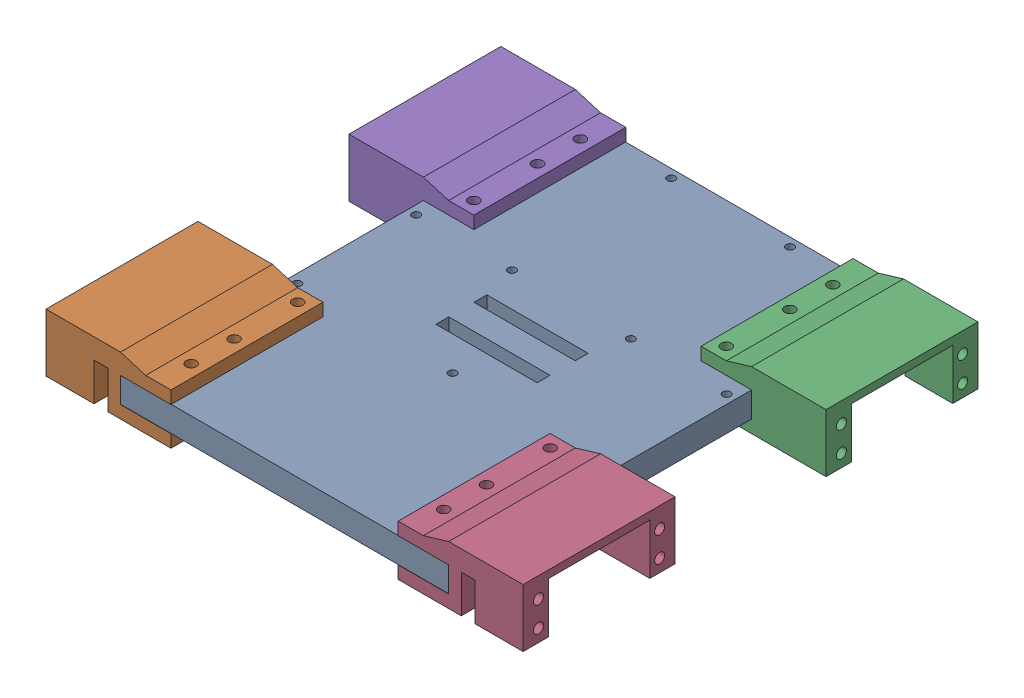
SolidWorks assembly Base_with_lateral_housings, configuration Default. Lengths in mm.
Overall size (189 23 180.2).
5 component instances, 3 part files, 8 mates.
Components (placement in the parent):
- Base_centric-1: Base_centric [Default] at origin size (130 10 180)
- Lateral_mount-1: Lateral_mount [Default] at (-94.5 -5 80.1) size (49.5 23 60.2)
- Lateral_mount-2: Lateral_mount [Default] at (94.5 -5 -80.1) x (-1 0 0) z (0 0 -1) size (49.5 23 60.2)
- Lateral_mount_mirrored-1: Lateral_mount_mirrored [Default] at (94.5 -5 80.1) size (49.5 23 60.2)
- Lateral_mount_mirrored-2: Lateral_mount_mirrored [Default] at (-94.5 -5 -80.1) x (-1 0 0) z (0 0 -1) size (49.5 23 60.2)
Mates (geometry in assembly coordinates):
- Concentric2: concentric anti-aligned: circle of Base_centric-1; circle of Lateral_mount_mirrored-1
- Coincident3: coincident anti-aligned: plane of Base_centric-1 through (0 10 0) normal (0 1 0); plane of Lateral_mount_mirrored-1 through (45 10 90.1) normal (0 -1 0)
- Concentric4: concentric anti-aligned: circle of Base_centric-1; circle of Lateral_mount-1
- Coincident6: coincident anti-aligned: plane of Base_centric-1 through (0 10 0) normal (0 1 0); plane of Lateral_mount-1 through (-45 10 90.1) normal (0 -1 0)
- Concentric6: concentric anti-aligned: circle of Base_centric-1; circle of Lateral_mount-2
- Coincident9: coincident anti-aligned: plane of Base_centric-1 through (0 10 0) normal (0 1 0); plane of Lateral_mount-2 through (45 10 -90.1) normal (0 -1 0)
- Concentric8: concentric anti-aligned: circle of Base_centric-1; circle of Lateral_mount_mirrored-2
- Coincident12: coincident anti-aligned: plane of Base_centric-1 through (0 10 0) normal (0 1 0); plane of Lateral_mount_mirrored-2 through (-45 10 -90.1) normal (0 -1 0)
